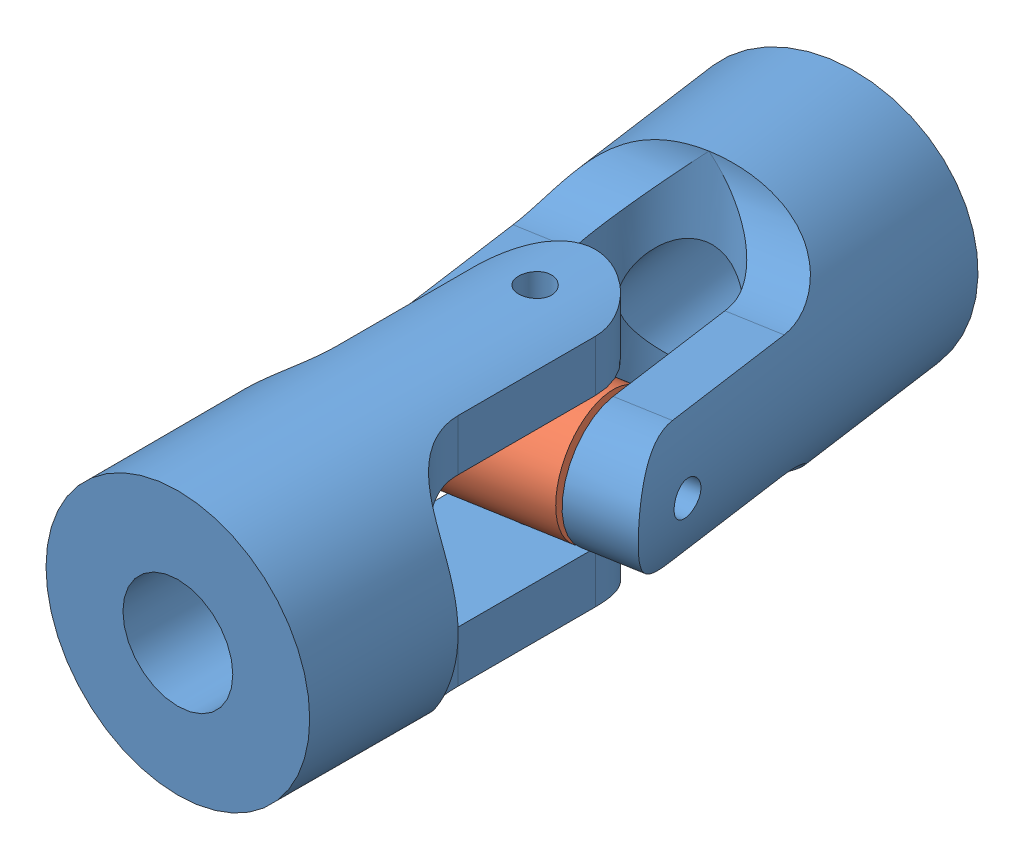
SolidWorks assembly 装配体3, configuration 默认. Lengths in mm.
Overall size (15.16 13.29 33.51).
3 component instances, 2 part files, 4 mates.
Components (placement in the parent):
- 可伸缩万向节1-1: 可伸缩万向节1 [默认] at (-21.567 3.1078 9.8941) size (12.58 12 19)
- 可伸缩万向节1-2: 可伸缩万向节1 [默认] at (-21.0963 3.2131 15.3514) x (0.006556 -0.999267 0.037708) z (-0.171171 -0.038274 -0.984498) size (12.58 12 19)
- 万向节中间球-1: 万向节中间球 [默认] at (-18.8576 3.1078 12.173) x (-0.171296 0 -0.98522) z (-0.98522 0 0.171296) size (5.5 5.5 5.5)
Mates (geometry in assembly coordinates):
- 同心1: concentric anti-aligned: cylinder of 可伸缩万向节1-2 through (-12.2074 3.1078 11.0167) axis (-0.98522 0 0.171296) radius 0.75; cylinder of 万向节中间球-1 through (-24.2763 3.1078 13.1151) axis (0.98522 0 -0.171296) radius 0.75
- 距离1: distance = 0.25 mm anti-aligned: plane of 万向节中间球-1 through (-24.2763 3.1078 13.1151) normal (-0.98522 0 0.171296); plane of 可伸缩万向节1-2 through (-25.6975 12.3521 6.4005) normal (0.98522 0 -0.171296)
- 同心2: concentric anti-aligned: cylinder of 可伸缩万向节1-1 through (-21.567 -6.3922 12.6441) axis (0 1 0) radius 0.75; cylinder of 万向节中间球-1 through (-21.567 5.8578 12.6441) axis (0 -1 0) radius 0.75
- 距离2: distance = 3 mm anti-aligned: plane of 可伸缩万向节1-1 through (-31.067 0.1078 9.8941) normal (0 1 0); cylinder of 万向节中间球-1 through (-24.2763 3.1078 13.1151) axis (0.98522 0 -0.171296) radius 2.75
